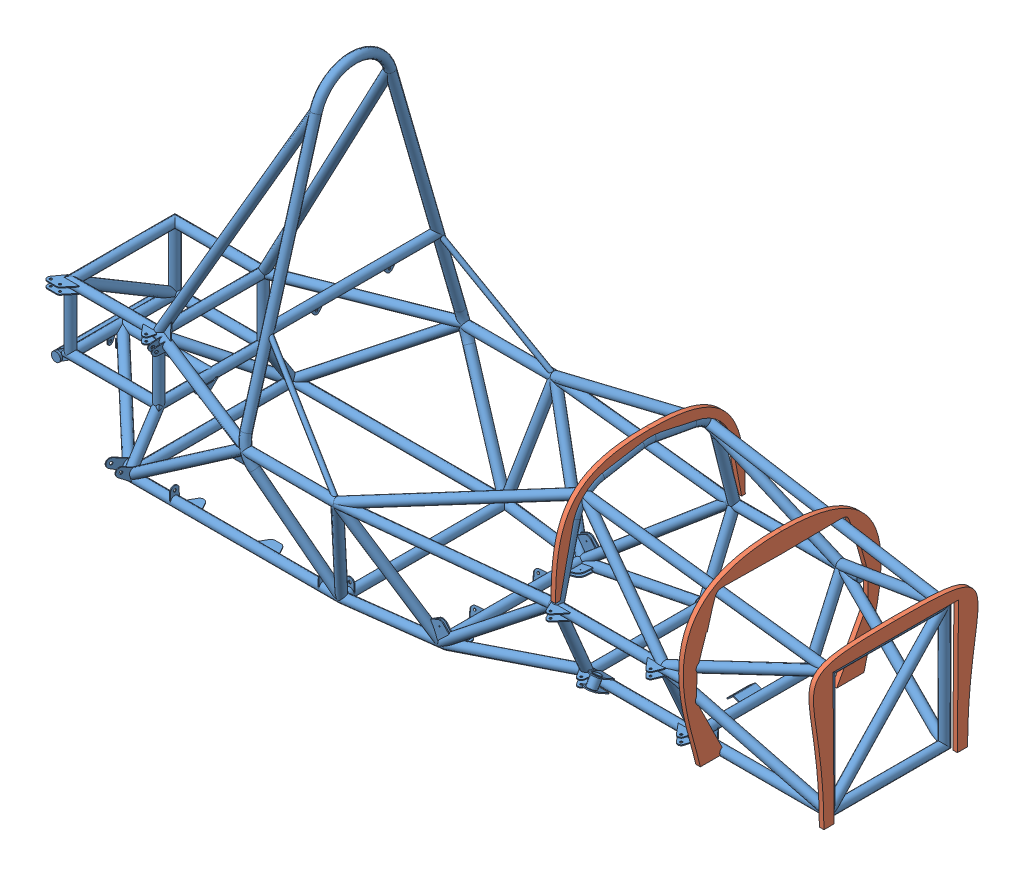
SolidWorks assembly Rib Assembly, configuration Default. Lengths in mm.
Overall size (2205.4 1117.81 1197.52).
2 component instances, 2 part files, 4 mates.
Components (placement in the parent):
- Body Sketches-1: Body Sketches [Default<As Machined>] at (1252.9478 672.4037 1690.465) size (2192.5 1117.81 1197.52)
- Ribs-1: Ribs [Default] at (1074.6779 672.4037 1690.465) x (0 0 -1) z (1 0 0) size (571.24 527.05 698.5)
Mates (geometry in assembly coordinates):
- InPlace1: in place: plane of Body Sketches-1 through (1074.6779 672.4037 1690.465) normal (1 0 0); plane of ? through (1074.6779 0 0) normal (1 0 0); moOrthogonalPlaneRef_w of Body Sketches-1 through (1074.6779 672.4037 1690.465) normal (1 0 0); line of ? through (-55 1074.6779 0) axis (0 0 1); plane of Body Sketches-1 through (1074.6779 672.4037 1690.465) normal (1 0 0); plane of ? through (1074.6779 0 0) normal (0 0 -1); plane of Body Sketches-1 through (1074.6779 672.4037 1690.465) normal (1 0 0); unknown of Ribs-1
- Coincident1: coincident aligned: plane of Body Sketches-1; plane of Ribs-1
- Coincident2: coincident aligned: moOrthogonalPlaneRef_w of Body Sketches-1 through (1074.6779 672.4037 1690.465) normal (0 1 0); plane of Ribs-1
- Coincident3: coincident anti-aligned: moOrthogonalPlaneRef_w of Body Sketches-1 through (1074.6779 672.4037 1690.465) normal (0 0 1); plane of Ribs-1 through (1074.6779 672.4037 1690.465) normal (0 0 -1)
